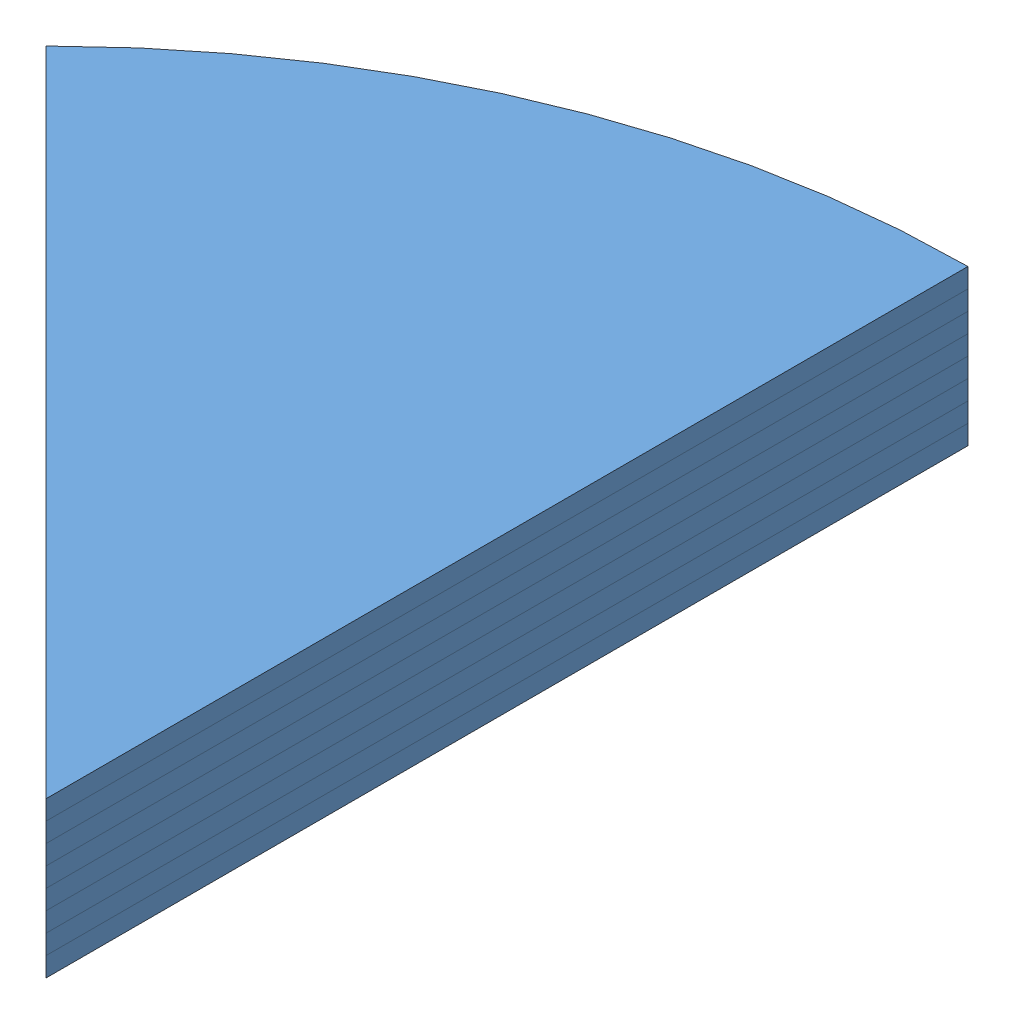
SolidWorks assembly large solar panel, configuration Default. Lengths in mm.
Overall size (671.75 160 950).
8 component instances, 1 part files, 21 mates.
Components (placement in the parent):
- large solar panel-10: large solar panel [Default] at (274.8121 -18.0732 512.7073) size (671.75 20 950)
- large solar panel-11: large solar panel [Default] at (274.8121 1.9268 512.7073) size (671.75 20 950)
- large solar panel-12: large solar panel [Default] at (274.8121 21.9268 512.7073) size (671.75 20 950)
- large solar panel-13: large solar panel [Default] at (274.8121 41.9268 512.7073) size (671.75 20 950)
- large solar panel-14: large solar panel [Default] at (274.8121 61.9268 512.7073) size (671.75 20 950)
- large solar panel-15: large solar panel [Default] at (274.8121 81.9268 512.7073) size (671.75 20 950)
- large solar panel-16: large solar panel [Default] at (274.8121 101.9268 512.7073) size (671.75 20 950)
- large solar panel-17: large solar panel [Default] at (274.8121 121.9268 512.7073) size (671.75 20 950)
Mates (geometry in assembly coordinates):
- Coincident1: coincident anti-aligned: plane of large solar panel-10 through (274.8121 1.9268 512.7073) normal (0 1 0); plane of ? through (274.8121 1.9268 512.7073) normal (0 -1 0)
- Coincident2: coincident aligned: line of large solar panel-10; line of ?
- Coincident3: coincident anti-aligned: plane of ? through (274.8121 21.9268 512.7073) normal (0 1 0); plane of ? through (274.8121 21.9268 512.7073) normal (0 -1 0)
- Coincident4: coincident aligned: line of ?; line of ?
- Coincident5: coincident anti-aligned: plane of ? through (274.8121 41.9268 512.7073) normal (0 1 0); plane of ? through (274.8121 41.9268 512.7073) normal (0 -1 0)
- Coincident6: coincident aligned: line of ?; line of ?
- Coincident7: coincident anti-aligned: plane of ? through (274.8121 61.9268 512.7073) normal (0 1 0); plane of ? through (274.8121 61.9268 512.7073) normal (0 -1 0)
- Coincident9: coincident aligned: line of ?; line of ?
- Coincident10: coincident anti-aligned: plane of ? through (274.8121 81.9268 512.7073) normal (0 1 0); plane of ? through (274.8121 81.9268 512.7073) normal (0 -1 0)
- Coincident11: coincident aligned: line of ?; line of ?
- Coincident12: coincident anti-aligned: plane of ? through (274.8121 101.9268 512.7073) normal (0 1 0); plane of ? through (274.8121 101.9268 512.7073) normal (0 -1 0)
- Coincident13: coincident aligned: line of ?; line of ?
- Coincident14: coincident anti-aligned: plane of ? through (274.8121 121.9268 512.7073) normal (0 1 0); plane of ? through (274.8121 121.9268 512.7073) normal (0 -1 0)
- Coincident15: coincident aligned: line of ?; line of ?
- Coincident18: coincident aligned: plane of ? through (274.8121 121.9268 512.7073) normal (-0.749782 0 0.661685); plane of ? through (274.8121 141.9268 512.7073) normal (-0.749782 0 0.661685)
- Coincident19: coincident aligned: plane of ? through (274.8121 101.9268 512.7073) normal (-0.749782 0 0.661685); plane of ? through (274.8121 121.9268 512.7073) normal (-0.749782 0 0.661685)
- Coincident20: coincident aligned: plane of ? through (274.8121 81.9268 512.7073) normal (-0.749782 0 0.661685); plane of ? through (274.8121 101.9268 512.7073) normal (-0.749782 0 0.661685)
- Coincident21: coincident aligned: plane of ? through (274.8121 61.9268 512.7073) normal (-0.749782 0 0.661685); plane of ? through (274.8121 81.9268 512.7073) normal (-0.749782 0 0.661685)
- Coincident22: coincident aligned: plane of ? through (274.8121 41.9268 512.7073) normal (-0.749782 0 0.661685); plane of ? through (274.8121 61.9268 512.7073) normal (-0.749782 0 0.661685)
- Coincident23: coincident aligned: plane of ? through (274.8121 21.9268 512.7073) normal (-0.749782 0 0.661685); plane of ? through (274.8121 41.9268 512.7073) normal (-0.749782 0 0.661685)
- Coincident24: coincident aligned: plane of large solar panel-10 through (274.8121 1.9268 512.7073) normal (-0.707107 0 0.707107); plane of ? through (274.8121 21.9268 512.7073) normal (-0.749782 0 0.661685)
